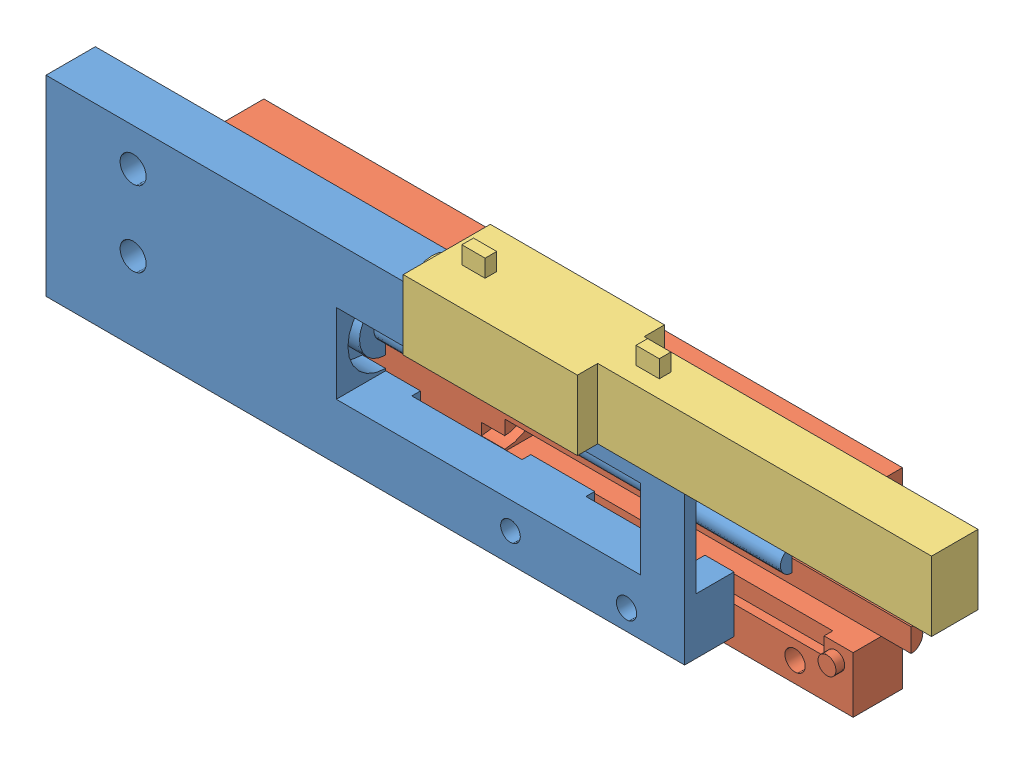
SolidWorks assembly full_finger_assembly, configuration Standard. Lengths in mm.
Overall size (158.82 55.09 33.29).
3 component instances, 3 part files, 0 mates.
Components (placement in the parent):
- finger_base_part1-1: finger_base_part1 [Valor predeterminado] at (164.1695 -25.9742 -13.5226) size (120 33 8.5)
- finger_base_part2-1: finger_base_part2 [Valor predeterminado] at (178.1926 -34.2587 -20.0226) size (120 33 10)
- finger_finger-1: finger_finger [Valor predeterminado] at (210.9876 -4.0208 -2.7369) size (90 18 15)
